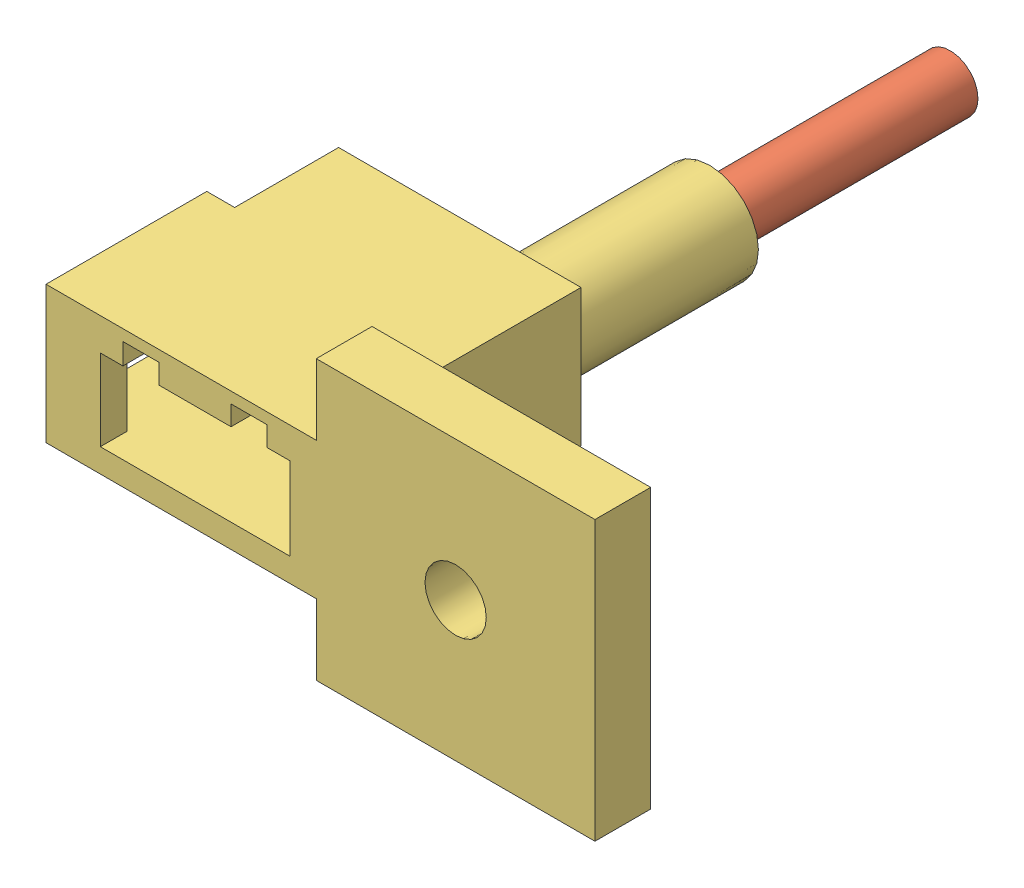
SolidWorks assembly Tool_length_switch, configuration Default. Lengths in mm.
Overall size (39.4 20 50.16).
3 component instances, 3 part files, 5 mates.
Components (placement in the parent):
- z-switch-1: z-switch [Default] at origin size (13.4 6.85 10.88)
- kinematic_dowel-1: kinematic_dowel [Default] at (-2.665 2.665 -33.1587) x (-0.587511 0.809216 0) z (0.809216 0.587511 0) size (4 25 4)
- Copy of housing-1: Copy of housing [Default] x (-1 0 0) z (0 0 -1) size (39.4 20 32.9)
Mates (geometry in assembly coordinates):
- Concentric1: concentric aligned: circle of z-switch-1; cylinder of kinematic_dowel-1 through (-2.665 2.665 -8.1587) axis (0 0 -1) radius 2
- InPlace1: in place: plane of z-switch-1 through (0 0 0) normal (0 0 -1); plane of Copy of housing-1 through (0 0 0) normal (0 0 -1); moOrthogonalPlaneRef_w of z-switch-1 through (0 0 0) normal (0 0 -1); plane of Copy of housing-1 through (0 0 0) normal (0 1 0); plane of z-switch-1 through (0 0 0) normal (0 0 -1); plane of Copy of housing-1 through (0 0 0) normal (-1 0 0); plane of z-switch-1 through (0 0 0) normal (0 0 -1); unknown of Copy of housing-1
- Coincident1: coincident aligned: plane of ?; plane of ?
- Coincident2: coincident aligned: moOrthogonalPlaneRef_w of z-switch-1 through (0 0 0) normal (0 1 0); plane of Part17^Assem5-1 through (0 0 0) normal (0 1 0)
- Coincident3: coincident anti-aligned: moOrthogonalPlaneRef_w of z-switch-1 through (0 0 0) normal (1 0 0); plane of Part17^Assem5-1 through (0 0 0) normal (-1 0 0)
